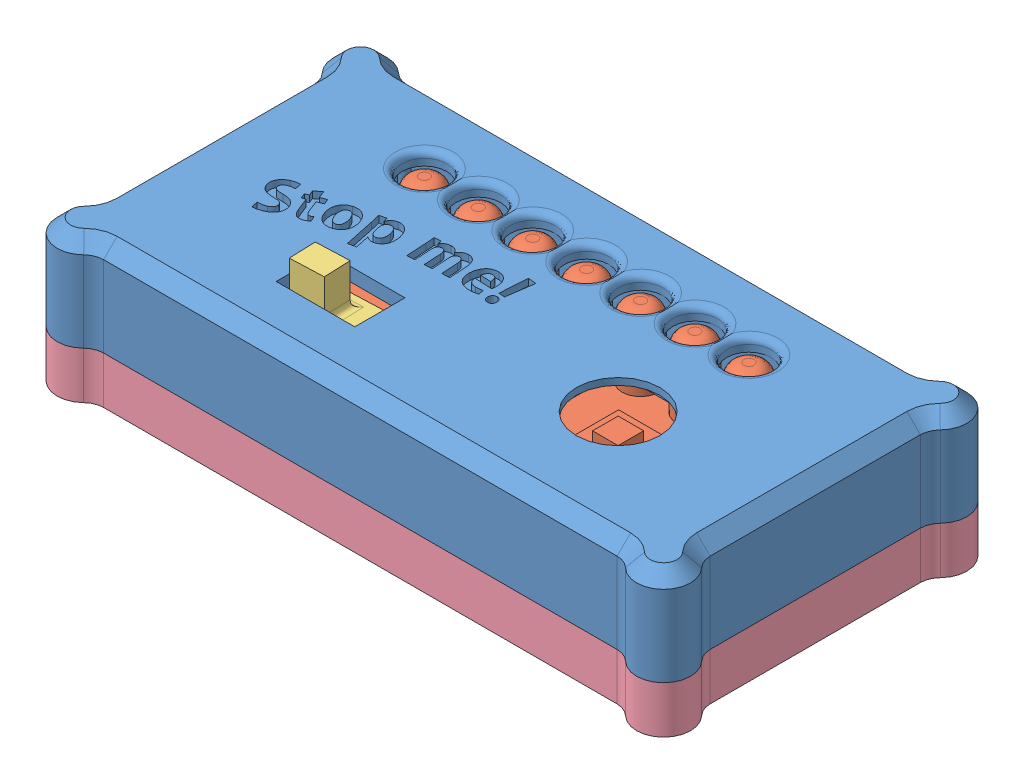
SolidWorks assembly assembly_final, configuration Default. Lengths in mm.
Overall size (94 23.7 49).
4 component instances, 4 part files, 8 mates.
Components (placement in the parent):
- asm_top-1: asm_top [Default] at (-8.1033 3.9836 94) size (94 20.05 49)
- asm_pcb-1: asm_pcb [Default] at (-7.7033 4.3081 94.4) size (82.16 19.1 37)
- button-1: button [Default] at (-25.5042 9.9836 105.1288) x (-0.03852 0 -0.999258) z (0.999258 0 -0.03852) size (8 6.7 18)
- asm_lid-1: asm_lid [Default] at (-8.1033 3.9836 94) size (94 19 49)
Mates (geometry in assembly coordinates):
- Coincident7: coincident: plane of asm_pcb-1 through (-7.7033 9.9836 94.4) normal (0 1 0); plane of button-1 through (-25.5042 9.9836 105.1288) normal (0 -1 0)
- Coincident8: coincident: point of assembly; point of assembly; moEndPointRef_w of asm_pcb-1; moEndPointRef_w of button-1
- Coincident9: coincident: plane of asm_top-1 through (-8.1033 2.9836 94) normal (0 -1 0); plane of asm_pcb-1 through (-7.7033 2.9836 94.4) normal (0 1 0)
- Coincident10: coincident: line of asm_top-1 through (23.2967 2.9836 109.4) axis (-1 0 0); line of asm_pcb-1 through (-38.7033 2.9836 109.4) axis (1 0 0)
- Coincident11: coincident: line of asm_top-1 through (23.2967 2.9836 78.6) axis (0 0 1); line of asm_pcb-1 through (23.2967 2.9836 109.4) axis (0 0 -1)
- Coincident12: coincident: plane of asm_top-1 through (-8.1033 -0.0164 94) normal (0 -1 0); plane of asm_lid-1 through (29.9977 -0.0164 68.5) normal (0 1 0)
- Coincident13: coincident: line of asm_top-1 through (29.9977 -0.0164 116.5) axis (-1 0 0); line of asm_lid-1 through (29.9977 -0.0164 116.5) axis (-1 0 0)
- Coincident14: coincident: line of asm_top-1 through (-53.1033 -0.0164 109.601) axis (0 0 -1); line of asm_lid-1 through (-53.1033 -0.0164 109.601) axis (0 0 -1)
